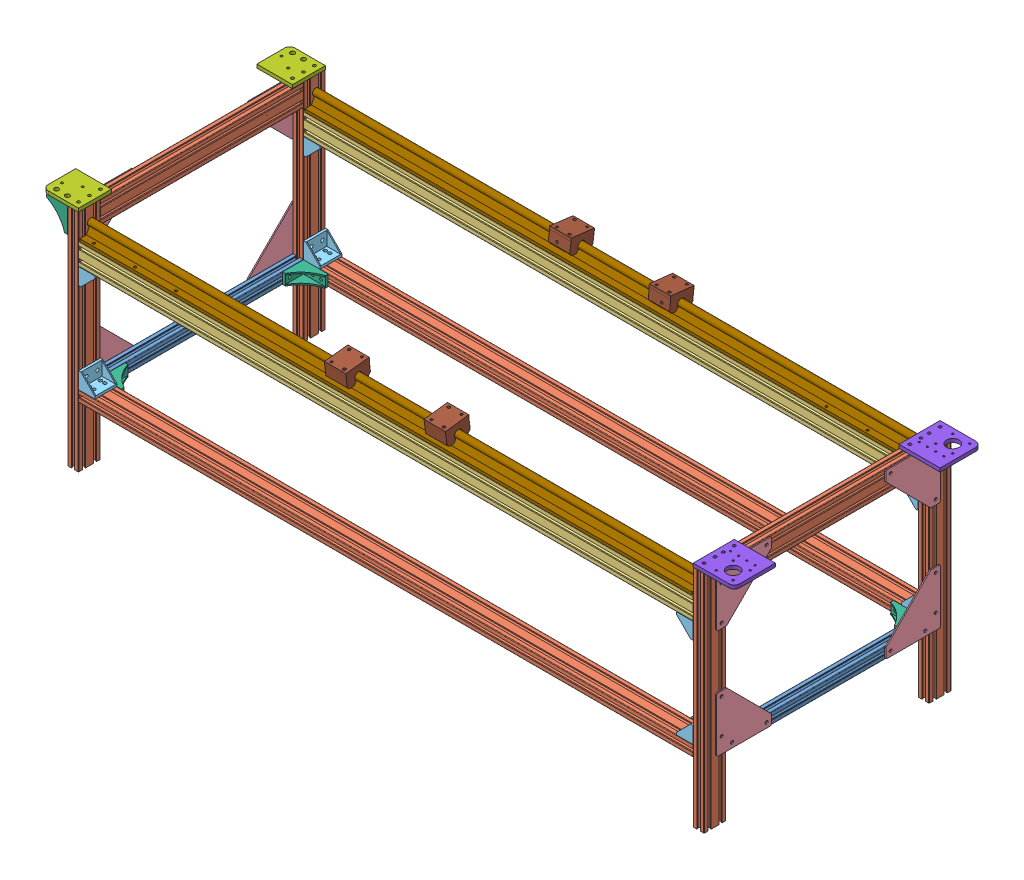
SolidWorks assembly SantaFe-Frame-Assy, configuration Default. Lengths in mm.
Overall size (1260 416.35 457.22).
69 component instances, 12 part files, 120 mates.
Components (placement in the parent):
- HFS5-2020-1: HFS5-2020 [370mm] at (0 110 0) size (20 20 370)
- HFS5-2020-2: HFS5-2020 [370mm] at (1140 110 0) size (20 20 370)
- HFS5-2040-7: HFS5-2040 [1120] at (1130 110 -20) x (0 -1 0) z (1 0 0) size (20 40 1120)
- HFS5-2040-8: HFS5-2040 [1120] at (10 110 390) x (0 1 0) z (-1 0 0) size (20 40 1120)
- HFS5-2040-1: HFS5-2040 [370mm] at (1140 380 370) size (20 40 370)
- HFS5-2040-2: HFS5-2040 [370mm] at (0 380 370) size (20 40 370)
- HFS5-4040-1120-1: HFS5-4040-1120 [Default] at (1130 334.5 390) x (0 0 -1) z (1 0 0) size (40 40 1120)
- HFS5-4040-1120-2: HFS5-4040-1120 [Default] at (1130 334.5 -20) x (0 0 -1) z (1 0 0) size (40 40 1120)
- HFS5-2040-3: HFS5-2040 [410mm] at (1140 400 390) x (1 0 0) z (0 1 0) size (20 40 410)
- HFS5-2040-4: HFS5-2040 [410mm] at (1140 -10 -20) x (1 0 0) z (0 -1 0) size (20 40 410)
- HFS5-2040-5: HFS5-2040 [410mm] at (0 -10 390) x (1 0 0) z (0 -1 0) size (20 40 410)
- HFS5-2040-6: HFS5-2040 [410mm] at (0 -10 -20) x (1 0 0) z (0 -1 0) size (20 40 410)
- SHPTCUL5-4: SHPTCUL5 [Default] at (1152 299 389) x (0 0 -1) z (1 0 0) size (100 100 2)
  - SHPTCUL5_Dummy-1: SHPTCUL5_Dummy [Default] at origin size (100 100 2)
- SHPTCUL5-5: SHPTCUL5 [Default] at (-10 299 389) x (0 0 -1) z (1 0 0) size (100 100 2)
  - SHPTCUL5_Dummy-1: SHPTCUL5_Dummy [Default] at origin size (100 100 2)
- SHPTCUL5-6: SHPTCUL5 [Default] at (1152 399 81) x (0 -1 0) z (1 0 0) size (100 100 2)
  - SHPTCUL5_Dummy-1: SHPTCUL5_Dummy [Default] at origin size (100 100 2)
- SHPTCUL5-7: SHPTCUL5 [Default] at (1152 101 289) x (0 1 0) z (1 0 0) size (100 100 2)
  - SHPTCUL5_Dummy-1: SHPTCUL5_Dummy [Default] at origin size (100 100 2)
- SHPTCUL5-8: SHPTCUL5 [Default] at (1152 201 -19) x (0 0 1) z (1 0 0) size (100 100 2)
  - SHPTCUL5_Dummy-1: SHPTCUL5_Dummy [Default] at origin size (100 100 2)
- SHPTCUL5-9: SHPTCUL5 [Default] at (-10 399 81) x (0 -1 0) z (1 0 0) size (100 100 2)
  - SHPTCUL5_Dummy-1: SHPTCUL5_Dummy [Default] at origin size (100 100 2)
- SHPTCUL5-10: SHPTCUL5 [Default] at (-10 201 -19) x (0 0 1) z (1 0 0) size (100 100 2)
  - SHPTCUL5_Dummy-1: SHPTCUL5_Dummy [Default] at origin size (100 100 2)
- SHPTCUL5-11: SHPTCUL5 [Default] at (-10 101 289) x (0 1 0) z (1 0 0) size (100 100 2)
  - SHPTCUL5_Dummy-1: SHPTCUL5_Dummy [Default] at origin size (100 100 2)
- Corner-Bracket-HBLFSDK5-1: Corner-Bracket-HBLFSDK5 [Default] at (1130 120 -20) x (0 0 1) z (-1 0 0) size (40 30 30)
- Corner-Bracket-HBLFSDK5-2: Corner-Bracket-HBLFSDK5 [Default] at (1130 120 390) x (0 0 1) z (-1 0 0) size (40 30 30)
- Corner-Bracket-HBLFSDK5-3: Corner-Bracket-HBLFSDK5 [Default] at (1130 314.5 390) x (0 0 1) z (0 -1 0) size (40 30 30)
- Corner-Bracket-HBLFSDK5-4: Corner-Bracket-HBLFSDK5 [Default] at (1130 314.5 -20) x (0 0 1) z (0 -1 0) size (40 30 30)
- Corner-Bracket-HBLFSDK5-5: Corner-Bracket-HBLFSDK5 [Default] at (10 314.5 -20) x (0 0 -1) z (0 -1 0) size (40 30 30)
- Corner-Bracket-HBLFSDK5-6: Corner-Bracket-HBLFSDK5 [Default] at (10 314.5 390) x (0 0 -1) z (0 -1 0) size (40 30 30)
- Corner-Bracket-HBLFSDK5-7: Corner-Bracket-HBLFSDK5 [Default] at (10 120 -20) x (0 0 -1) z (1 0 0) size (40 30 30)
- Corner-Bracket-HBLFSDK5-8: Corner-Bracket-HBLFSDK5 [Default] at (10 120 390) x (0 0 -1) z (1 0 0) size (40 30 30)
- HBLFSSW5-3: HBLFSSW5 [Default] at (10 110 370) x (0 -1 0) z (1 0 0) size (20 45.8 38.8)
  - HBLFSSW5hblfsn5-1: HBLFSSW5hblfsn5 [Default] at origin size (20 45.8 38.8)
- HBLFSSW5-4: HBLFSSW5 [Default] at (10 110 0) x (0 -1 0) z (0 0 1) size (20 45.8 38.8)
  - HBLFSSW5hblfsn5-1: HBLFSSW5hblfsn5 [Default] at origin size (20 45.8 38.8)
- HBLFSSW5-5: HBLFSSW5 [Default] at (1130 110 0) x (0 1 0) z (0 0 1) size (20 45.8 38.8)
  - HBLFSSW5hblfsn5-1: HBLFSSW5hblfsn5 [Default] at origin size (20 45.8 38.8)
- HBLFSSW5-6: HBLFSSW5 [Default] at (1130 110 370) x (0 -1 0) z (0 0 -1) size (20 45.8 38.8)
  - HBLFSSW5hblfsn5-1: HBLFSSW5hblfsn5 [Default] at origin size (20 45.8 38.8)
- HBLFSSW5-7: HBLFSSW5 [Default] at (-10 400 400) x (0 0 -1) z (-1 0 0) size (20 45.8 38.8)
  - HBLFSSW5hblfsn5-1: HBLFSSW5hblfsn5 [Default] at origin size (20 45.8 38.8)
- HBLFSSW5-8: HBLFSSW5 [Default] at (-10 400 -30) x (0 0 -1) z (-1 0 0) size (20 45.8 38.8)
  - HBLFSSW5hblfsn5-1: HBLFSSW5hblfsn5 [Default] at origin size (20 45.8 38.8)
- Idler-Plate-1: Idler-Plate [Default] at (10 406.35 20) x (0 0 -1) z (-1 0 0) size (60 6.35 65)
- Idler-Plate-2: Idler-Plate [Default] at (10 400 350) x (0 0 1) z (-1 0 0) size (60 6.35 65)
- Stepper-Plate-1: Stepper-Plate [Default] at (1130 400 35) x (0 0 -1) z (1 0 0) size (75 6.35 75)
- Stepper-Plate-2: Stepper-Plate [Default] at (1130 406.35 335) x (0 0 1) z (1 0 0) size (75 6.35 75)
- X-Axis-Slide-Assy-1: X-Axis-Slide-Assy [Default] at (202.5 376.5 390) x (0 0 1) z (0 1 0) size (46.21 1115 42.58) (flexible)
  - AWMU-12-1: AWMU-12 [Default] at origin size (40 1115 28)
  - OJUM-06-12-1: OJUM-06-12 [Mirror] at (0 460.2515 0) x (-0.991917 0 0.126885) z (-0.126885 0 -0.991917) size (43 39 28)
    - OJUM-06-12-1: OJUM-06-12 [Default] at origin size (15.6 31 13.94)
    - OJUM-06-12_1-1: OJUM-06-12_1 [Mirror] at origin size (43 39 28)
  - OJUM-06-12-2: OJUM-06-12 [Default] at (0 278.4523 0) x (-0.99383 0 0.110917) z (-0.110917 0 -0.99383) size (43 39 28)
    - OJUM-06-12-1: OJUM-06-12 [Default] at origin size (15.6 31 13.94)
    - OJUM-06-12_1-1: OJUM-06-12_1 [Default] at origin size (43 39 28)
- X-Axis-Slide-Assy-2: X-Axis-Slide-Assy [Default] at (937.5 376.5 -20) x (0 0 -1) z (0 1 0) size (46.21 1115 42.58) (flexible)
  - AWMU-12-1: AWMU-12 [Default] at origin size (40 1115 28)
  - OJUM-06-12-1: OJUM-06-12 [Mirror] at (0 460.2515 0) x (-0.991917 0 0.126885) z (-0.126885 0 -0.991917) size (43 39 28)
    - OJUM-06-12-1: OJUM-06-12 [Default] at origin size (15.6 31 13.94)
    - OJUM-06-12_1-1: OJUM-06-12_1 [Mirror] at origin size (43 39 28)
  - OJUM-06-12-2: OJUM-06-12 [Default] at (0 278.4523 0) x (-0.99383 0 0.110917) z (-0.110917 0 -0.99383) size (43 39 28)
    - OJUM-06-12-1: OJUM-06-12 [Default] at origin size (15.6 31 13.94)
    - OJUM-06-12_1-1: OJUM-06-12_1 [Default] at origin size (43 39 28)
- SpacerStick-1: SpacerStick [Default] at (60 217.25 -36.825) x (-1 0 0) z (0 0 -1) size (65 194.5 3.17) (hidden)
Mates (geometry in assembly coordinates):
- Coincident13: coincident anti-aligned: plane of HFS5-2020-2 through (1130 113.3 370) normal (-1 0 0); plane of HFS5-2040-8 through (1130 101 409) normal (1 0 0)
- Coincident57: coincident aligned: plane of HFS5-4040-1120-1 through (10 314.5 397) normal (0 -1 0); plane of HFS5-4040-1120-2 through (10 314.5 -13) normal (0 -1 0)
- Coincident58: coincident anti-aligned: plane of HFS5-2040-8 through (1130 101 409) normal (1 0 0); plane of HFS5-2040-3 through (1130 -10 383) normal (-1 0 0)
- Coincident60: coincident anti-aligned: plane of HFS5-2020-2 through (1136.5 109.3464 370) normal (0 0 1); plane of HFS5-2040-3 through (1137 -10 370) normal (0 0 -1)
- Coincident62: coincident anti-aligned: plane of HFS5-4040-1120-1 through (1130 315.5 409) normal (1 0 0); plane of HFS5-2040-3 through (1130 -10 383) normal (-1 0 0)
- Coincident63: coincident aligned: plane of HFS5-4040-1120-1 through (10 341.5 410) normal (0 0 1); plane of HFS5-2040-3 through (1131 -10 410) normal (0 0 1)
- Coincident64: coincident anti-aligned: plane of HFS5-2040-1 through (1131 361 370) normal (0 0 1); plane of HFS5-2040-3 through (1137 -10 370) normal (0 0 -1)
- Coincident65: coincident aligned: plane of HFS5-2040-1 through (1150 373 0) normal (1 0 0); plane of HFS5-2040-3 through (1150 -10 377) normal (1 0 0)
- Coincident66: coincident aligned: plane of HFS5-2040-1 through (1137 400 0) normal (0 1 0); plane of HFS5-2040-3 through (1131 400 409) normal (0 1 0)
- Coincident67: coincident anti-aligned: plane of HFS5-2020-2 through (1136.5 109.3464 0) normal (0 0 -1); plane of HFS5-2040-4 through (1137 400 0) normal (0 0 1)
- Coincident68: coincident aligned: plane of HFS5-2020-2 through (1150 113.3 370) normal (1 0 0); plane of HFS5-2040-4 through (1150 400 -27) normal (1 0 0)
- Coincident70: coincident anti-aligned: plane of HFS5-2020-1 through (-3.5 109.3464 370) normal (0 0 1); plane of HFS5-2040-5 through (3 400 370) normal (0 0 -1)
- Coincident71: coincident aligned: plane of HFS5-2020-1 through (-10 113.3 370) normal (-1 0 0); plane of HFS5-2040-5 through (-10 400 397) normal (-1 0 0)
- Coincident74: coincident anti-aligned: plane of HFS5-2040-8 through (10 101 409) normal (-1 0 0); plane of HFS5-2040-5 through (10 400 383) normal (1 0 0)
- Coincident76: coincident anti-aligned: plane of HFS5-2040-2 through (-9 361 0) normal (0 0 -1); plane of HFS5-2040-6 through (9 400 0) normal (0 0 1)
- Coincident77: coincident aligned: plane of HFS5-2040-2 through (9 400 0) normal (0 1 0); plane of HFS5-2040-5 through (-9 400 371) normal (0 1 0)
- Coincident78: coincident anti-aligned: plane of HFS5-2020-1 through (-3.5 109.3464 0) normal (0 0 -1); plane of HFS5-2040-6 through (-3 400 0) normal (0 0 1)
- Coincident79: coincident aligned: plane of HFS5-2020-1 through (-10 113.3 370) normal (-1 0 0); plane of HFS5-2040-6 through (-10 400 -13) normal (-1 0 0)
- Coincident81: coincident aligned: plane of HFS5-2040-7 through (10 113 -40) normal (0 0 -1); plane of HFS5-2040-6 through (3 400 -40) normal (0 0 -1)
- Coincident85: coincident anti-aligned: plane of HFS5-2040-7 through (10 119 -1) normal (-1 0 0); plane of HFS5-2040-6 through (10 400 -27) normal (1 0 0)
- Coincident86: coincident aligned: plane of HFS5-2040-2 through (-10 387 0) normal (-1 0 0); plane of HFS5-2040-5 through (-10 400 397) normal (-1 0 0)
- Distance2: distance = 45.5 mm aligned: plane of HFS5-2040-5 through (-9 400 371) normal (0 1 0); plane of HFS5-4040-1120-1 through (10 354.5 403) normal (0 1 0)
- Coincident88: coincident aligned: plane of HFS5-4040-1120-2 through (10 327.5 -40) normal (0 0 -1); plane of HFS5-2040-6 through (3 400 -40) normal (0 0 -1)
- Coincident89: coincident anti-aligned: plane of HFS5-4040-1120-2 through (10 315.5 -1) normal (-1 0 0); plane of HFS5-2040-6 through (10 400 -27) normal (1 0 0)
- Coincident108: coincident aligned: plane of HFS5-2040-8 through (1130 113 410) normal (0 0 1); plane of HFS5-2040-3 through (1131 -10 410) normal (0 0 1)
- Coincident111: coincident aligned: plane of HFS5-2040-7 through (10 113 -40) normal (0 0 -1); plane of HFS5-2040-4 through (1143 400 -40) normal (0 0 -1)
- Coincident113: coincident anti-aligned: plane of HFS5-2040-1 through (1150 373 0) normal (1 0 0); plane of SHPTCUL5-4/SHPTCUL5_Dummy-1 through (1150 299 389) normal (-1 0 0)
- Coincident114: coincident: line of HFS5-2040-1 through (1150 399 0) axis (0 0 1); plane of SHPTCUL5-4/SHPTCUL5_Dummy-1 through (1150 399 291) normal (0 1 0)
- Coincident115: coincident: line of HFS5-2040-3 through (1150 -10 371) axis (0 1 0); point of SHPTCUL5-4/SHPTCUL5_Dummy-1
- Coincident116: coincident anti-aligned: plane of HFS5-2040-5 through (-10 400 397) normal (-1 0 0); plane of SHPTCUL5-5/SHPTCUL5_Dummy-1 through (-10 299 389) normal (1 0 0)
- Coincident117: coincident: line of HFS5-2040-2 through (-10 399 0) axis (0 0 1); plane of SHPTCUL5-5/SHPTCUL5_Dummy-1 through (-12 399 291) normal (0 1 0)
- Coincident118: coincident: line of HFS5-2040-5 through (-10 400 371) axis (0 -1 0); point of SHPTCUL5-5/SHPTCUL5_Dummy-1
- Coincident119: coincident anti-aligned: plane of HFS5-2040-1 through (1150 373 0) normal (1 0 0); plane of SHPTCUL5-6/SHPTCUL5_Dummy-1 through (1150 399 81) normal (-1 0 0)
- Coincident122: coincident: line of HFS5-2040-1 through (1150 399 0) axis (0 0 1); plane of SHPTCUL5-6/SHPTCUL5_Dummy-1 through (1150 399 -17) normal (0 1 0)
- Coincident123: coincident: line of HFS5-2040-4 through (1150 400 -1) axis (0 -1 0); point of SHPTCUL5-6/SHPTCUL5_Dummy-1
- Coincident124: coincident anti-aligned: plane of HFS5-2040-3 through (1150 -10 397) normal (1 0 0); plane of SHPTCUL5-7/SHPTCUL5_Dummy-1 through (1150 101 289) normal (-1 0 0)
- Coincident125: coincident anti-aligned: plane of HFS5-2040-4 through (1150 400 -27) normal (1 0 0); plane of SHPTCUL5-8/SHPTCUL5_Dummy-1 through (1150 201 -19) normal (-1 0 0)
- Coincident126: coincident: line of HFS5-2020-2 through (1150 101 370) axis (0 0 -1); plane of SHPTCUL5-7/SHPTCUL5_Dummy-1 through (1150 101 387) normal (0 -1 0)
- Coincident127: coincident: line of HFS5-2040-3 through (1150 -10 371) axis (0 1 0); point of SHPTCUL5-7/SHPTCUL5_Dummy-1
- Coincident128: coincident: line of HFS5-2020-2 through (1150 101 370) axis (0 0 -1); plane of SHPTCUL5-8/SHPTCUL5_Dummy-1 through (1150 101 79) normal (0 -1 0)
- Coincident129: coincident: line of HFS5-2040-4 through (1150 400 -1) axis (0 -1 0); point of SHPTCUL5-8/SHPTCUL5_Dummy-1
- Coincident130: coincident anti-aligned: plane of HFS5-2040-2 through (-10 387 0) normal (-1 0 0); plane of SHPTCUL5-9/SHPTCUL5_Dummy-1 through (-10 399 81) normal (1 0 0)
- Coincident131: coincident: line of HFS5-2040-2 through (-10 399 0) axis (0 0 1); plane of SHPTCUL5-9/SHPTCUL5_Dummy-1 through (-12 399 -17) normal (0 1 0)
- Coincident132: coincident: line of HFS5-2040-6 through (-10 400 -1) axis (0 -1 0); point of SHPTCUL5-9/SHPTCUL5_Dummy-1
- Coincident133: coincident: line of HFS5-2020-1 through (-10 101 370) axis (0 0 -1); plane of SHPTCUL5-10/SHPTCUL5_Dummy-1 through (-12 101 79) normal (0 -1 0)
- Coincident134: coincident anti-aligned: plane of HFS5-2020-1 through (-10 106.7 370) normal (-1 0 0); plane of SHPTCUL5-10/SHPTCUL5_Dummy-1 through (-10 201 -19) normal (1 0 0)
- Coincident135: coincident: line of HFS5-2040-6 through (-10 400 -1) axis (0 -1 0); point of SHPTCUL5-10/SHPTCUL5_Dummy-1
- Coincident136: coincident anti-aligned: plane of HFS5-2040-5 through (-10 400 397) normal (-1 0 0); plane of SHPTCUL5-11/SHPTCUL5_Dummy-1 through (-10 101 289) normal (1 0 0)
- Coincident137: coincident: line of HFS5-2020-1 through (-10 101 370) axis (0 0 -1); plane of SHPTCUL5-11/SHPTCUL5_Dummy-1 through (-12 101 387) normal (0 -1 0)
- Coincident138: coincident: line of HFS5-2040-5 through (-10 400 371) axis (0 -1 0); point of SHPTCUL5-11/SHPTCUL5_Dummy-1
- Coincident139: coincident anti-aligned: plane of HFS5-2040-4 through (1130 400 -13) normal (-1 0 0); plane of Corner-Bracket-HBLFSDK5-4 through (1130 284.5 0) normal (1 0 0)
- Coincident140: coincident anti-aligned: plane of HFS5-4040-1120-2 through (10 314.5 -13) normal (0 -1 0); plane of Corner-Bracket-HBLFSDK5-4 through (1130 314.5 0) normal (0 1 0)
- Coincident141: coincident aligned: plane of HFS5-4040-1120-2 through (10 327.5 -40) normal (0 0 -1); plane of Corner-Bracket-HBLFSDK5-4 through (1130 314.5 -40) normal (0 0 -1)
- Coincident142: coincident aligned: plane of HFS5-2040-4 through (1131 400 -40) normal (0 0 -1); plane of Corner-Bracket-HBLFSDK5-1 through (1130 120 -40) normal (0 0 -1)
- Coincident143: coincident anti-aligned: plane of HFS5-2040-4 through (1130 400 -13) normal (-1 0 0); plane of Corner-Bracket-HBLFSDK5-1 through (1130 120 0) normal (1 0 0)
- Coincident144: coincident anti-aligned: plane of HFS5-2040-7 through (10 120 -27) normal (0 1 0); plane of Corner-Bracket-HBLFSDK5-1 through (1100 120 0) normal (0 -1 0)
- Coincident145: coincident anti-aligned: plane of HFS5-2040-3 through (1130 -10 383) normal (-1 0 0); plane of Corner-Bracket-HBLFSDK5-2 through (1130 120 410) normal (1 0 0)
- Coincident146: coincident anti-aligned: plane of HFS5-2040-8 through (1130 120 397) normal (0 1 0); plane of Corner-Bracket-HBLFSDK5-2 through (1100 120 410) normal (0 -1 0)
- Coincident147: coincident aligned: plane of HFS5-2040-3 through (1131 -10 410) normal (0 0 1); plane of Corner-Bracket-HBLFSDK5-2 through (1130 120 410) normal (0 0 1)
- Coincident148: coincident anti-aligned: plane of HFS5-2040-3 through (1130 -10 383) normal (-1 0 0); plane of Corner-Bracket-HBLFSDK5-3 through (1130 284.5 410) normal (1 0 0)
- Coincident149: coincident anti-aligned: plane of HFS5-4040-1120-1 through (10 314.5 397) normal (0 -1 0); plane of Corner-Bracket-HBLFSDK5-3 through (1130 314.5 410) normal (0 1 0)
- Coincident150: coincident aligned: plane of HFS5-4040-1120-1 through (10 341.5 410) normal (0 0 1); plane of Corner-Bracket-HBLFSDK5-3 through (1130 314.5 410) normal (0 0 1)
- Coincident151: coincident anti-aligned: plane of HFS5-2040-8 through (1130 120 397) normal (0 1 0); plane of Corner-Bracket-HBLFSDK5-8 through (40 120 370) normal (0 -1 0)
- Coincident152: coincident anti-aligned: plane of HFS5-2040-5 through (10 400 383) normal (1 0 0); plane of Corner-Bracket-HBLFSDK5-8 through (10 120 370) normal (-1 0 0)
- Coincident153: coincident aligned: plane of HFS5-2040-8 through (1130 113 410) normal (0 0 1); plane of Corner-Bracket-HBLFSDK5-8 through (10 120 410) normal (0 0 1)
- Coincident154: coincident anti-aligned: plane of HFS5-2040-7 through (10 120 -27) normal (0 1 0); plane of Corner-Bracket-HBLFSDK5-7 through (40 120 -40) normal (0 -1 0)
- Coincident155: coincident aligned: plane of HFS5-2040-7 through (10 113 -40) normal (0 0 -1); plane of Corner-Bracket-HBLFSDK5-7 through (10 120 -40) normal (0 0 -1)
- Coincident156: coincident anti-aligned: plane of HFS5-2040-6 through (10 400 -27) normal (1 0 0); plane of Corner-Bracket-HBLFSDK5-7 through (10 120 -40) normal (-1 0 0)
- Coincident157: coincident anti-aligned: plane of HFS5-4040-1120-2 through (10 314.5 -33) normal (0 -1 0); plane of Corner-Bracket-HBLFSDK5-5 through (10 314.5 -40) normal (0 1 0)
- Coincident158: coincident anti-aligned: plane of HFS5-2040-6 through (10 400 -27) normal (1 0 0); plane of Corner-Bracket-HBLFSDK5-5 through (10 284.5 -40) normal (-1 0 0)
- Coincident159: coincident aligned: plane of HFS5-2040-6 through (-9 400 -40) normal (0 0 -1); plane of Corner-Bracket-HBLFSDK5-5 through (10 314.5 -40) normal (0 0 -1)
- Coincident160: coincident anti-aligned: plane of HFS5-4040-1120-1 through (10 314.5 397) normal (0 -1 0); plane of Corner-Bracket-HBLFSDK5-6 through (10 314.5 370) normal (0 1 0)
- Coincident161: coincident anti-aligned: plane of HFS5-2040-5 through (10 400 383) normal (1 0 0); plane of Corner-Bracket-HBLFSDK5-6 through (10 284.5 370) normal (-1 0 0)
- Coincident162: coincident aligned: plane of HFS5-4040-1120-1 through (10 341.5 410) normal (0 0 1); plane of Corner-Bracket-HBLFSDK5-6 through (10 314.5 410) normal (0 0 1)
- Coincident188: coincident aligned: plane of HFS5-2040-8 through (1130 120 397) normal (0 1 0); plane of HBLFSSW5-3/HBLFSSW5hblfsn5-1 through (14.5286 120 326) normal (0 1 0)
- Coincident189: coincident anti-aligned: plane of HFS5-2020-1 through (10 106.7 370) normal (1 0 0); plane of HBLFSSW5-3/HBLFSSW5hblfsn5-1 through (10 110 370) normal (-1 0 0)
- Coincident190: coincident anti-aligned: plane of HFS5-2040-8 through (1130 119 370) normal (0 0 -1); plane of HBLFSSW5-3/HBLFSSW5hblfsn5-1 through (9.2 120 370) normal (0 0 1)
- Coincident191: coincident aligned: plane of HFS5-2040-7 through (10 120 -27) normal (0 1 0); plane of HBLFSSW5-4/HBLFSSW5hblfsn5-1 through (54 120 4.5286) normal (0 1 0)
- Coincident192: coincident anti-aligned: plane of HFS5-2020-1 through (10 106.7 370) normal (1 0 0); plane of HBLFSSW5-4/HBLFSSW5hblfsn5-1 through (10 120 -0.8) normal (-1 0 0)
- Coincident193: coincident anti-aligned: plane of HFS5-2040-7 through (10 119 0) normal (0 0 1); plane of HBLFSSW5-4/HBLFSSW5hblfsn5-1 through (10 110 0) normal (0 0 -1)
- Coincident194: coincident aligned: plane of HFS5-2040-8 through (1130 120 397) normal (0 1 0); plane of HBLFSSW5-6/HBLFSSW5hblfsn5-1 through (1086 120 365.4714) normal (0 1 0)
- Coincident195: coincident anti-aligned: plane of HFS5-2040-8 through (1130 119 370) normal (0 0 -1); plane of HBLFSSW5-6/HBLFSSW5hblfsn5-1 through (1130 110 370) normal (0 0 1)
- Coincident196: coincident anti-aligned: plane of HFS5-2020-2 through (1130 113.3 370) normal (-1 0 0); plane of HBLFSSW5-6/HBLFSSW5hblfsn5-1 through (1130 120 370.8) normal (1 0 0)
- Coincident197: coincident aligned: plane of HFS5-2040-7 through (10 120 -27) normal (0 1 0); plane of HBLFSSW5-5/HBLFSSW5hblfsn5-1 through (1086 120 4.5286) normal (0 1 0)
- Coincident198: coincident anti-aligned: plane of HFS5-2040-7 through (10 119 0) normal (0 0 1); plane of HBLFSSW5-5/HBLFSSW5hblfsn5-1 through (1130 110 0) normal (0 0 -1)
- Coincident199: coincident anti-aligned: plane of HFS5-2020-2 through (1130 113.3 370) normal (-1 0 0); plane of HBLFSSW5-5/HBLFSSW5hblfsn5-1 through (1130 100 -0.8) normal (1 0 0)
- Coincident200: coincident anti-aligned: plane of HFS5-2040-6 through (-10 400 -33) normal (-1 0 0); plane of HBLFSSW5-8/HBLFSSW5hblfsn5-1 through (-10 400 -30) normal (1 0 0)
- Coincident201: coincident aligned: plane of HFS5-2040-6 through (-9 400 -39) normal (0 1 0); plane of HBLFSSW5-8/HBLFSSW5hblfsn5-1 through (-9.2 400 -20) normal (0 1 0)
- Coincident202: coincident aligned: plane of HFS5-2040-6 through (-9 400 -40) normal (0 0 -1); plane of HBLFSSW5-8/HBLFSSW5hblfsn5-1 through (-14.5286 356 -40) normal (0 0 -1)
- Coincident203: coincident anti-aligned: plane of HFS5-2040-5 through (-10 400 409) normal (-1 0 0); plane of HBLFSSW5-7/HBLFSSW5hblfsn5-1 through (-10 400 400) normal (1 0 0)
- Coincident204: coincident aligned: plane of HFS5-2040-5 through (-9 400 371) normal (0 1 0); plane of HBLFSSW5-7/HBLFSSW5hblfsn5-1 through (-9.2 400 410) normal (0 1 0)
- Coincident205: coincident aligned: plane of HFS5-2040-5 through (-3 400 410) normal (0 0 1); plane of HBLFSSW5-7/HBLFSSW5hblfsn5-1 through (-14.5286 356 410) normal (0 0 1)
- Coincident206: coincident anti-aligned: plane of HFS5-2040-5 through (-9 400 371) normal (0 1 0); plane of Idler-Plate-2 through (10 400 350) normal (0 -1 0)
- Concentric2: concentric aligned: cylinder of HFS5-2040-5 through (0 1190 400) axis (0 -1 0) radius 2.1; cylinder of Idler-Plate-2 through (0 406.35 400) axis (0 -1 0) radius 2.625
- Concentric3: concentric aligned: cylinder of HFS5-2040-5 through (0 1190 380) axis (0 -1 0) radius 2.1; cylinder of Idler-Plate-2 through (0 406.35 380) axis (0 -1 0) radius 2.625
- Coincident207: coincident anti-aligned: plane of HFS5-2040-6 through (-9 400 -39) normal (0 1 0); plane of Idler-Plate-1 through (10 400 20) normal (0 -1 0)
- Concentric4: concentric anti-aligned: cylinder of HFS5-2040-6 through (0 1190 -30) axis (0 -1 0) radius 2.1; cylinder of Idler-Plate-1 through (0 400 -30) axis (0 1 0) radius 2.625
- Concentric5: concentric anti-aligned: cylinder of HFS5-2040-6 through (0 1190 -10) axis (0 -1 0) radius 2.1; cylinder of Idler-Plate-1 through (0 400 -10) axis (0 1 0) radius 2.625
- Coincident208: coincident anti-aligned: plane of HFS5-2040-4 through (1131 400 -39) normal (0 1 0); plane of Stepper-Plate-1 through (1130 400 35) normal (0 -1 0)
- Concentric6: concentric aligned: cylinder of HFS5-2040-4 through (1140 1190 -30) axis (0 -1 0) radius 2.1; cylinder of Stepper-Plate-1 through (1140 406.35 -30) axis (0 -1 0) radius 2.625
- Concentric7: concentric aligned: cylinder of HFS5-2040-4 through (1140 1190 -10) axis (0 -1 0) radius 2.1; cylinder of Stepper-Plate-1 through (1140 406.35 -10) axis (0 -1 0) radius 2.625
- Coincident209: coincident anti-aligned: plane of HFS5-2040-3 through (1131 400 409) normal (0 1 0); plane of Stepper-Plate-2 through (1130 400 335) normal (0 -1 0)
- Concentric8: concentric aligned: cylinder of HFS5-2040-3 through (1140 -800 400) axis (0 1 0) radius 2.1; cylinder of Stepper-Plate-2 through (1140 400 400) axis (0 1 0) radius 2.625
- Concentric9: concentric aligned: cylinder of HFS5-2040-3 through (1140 -800 380) axis (0 1 0) radius 2.1; cylinder of Stepper-Plate-2 through (1140 400 380) axis (0 1 0) radius 2.625
- Coincident210: coincident aligned: plane of HFS5-2040-1 through (1137 400 0) normal (0 1 0); plane of HFS5-2040-4 through (1131 400 -39) normal (0 1 0)
- Coincident214: coincident aligned: plane of HFS5-2040-3 through (1131 400 409) normal (0 1 0); plane of HFS5-2040-5 through (-9 400 371) normal (0 1 0)
- Coincident215: coincident aligned: plane of HFS5-2040-2 through (9 400 0) normal (0 1 0); plane of HFS5-2040-6 through (-9 400 -39) normal (0 1 0)
- Coincident216: coincident aligned: plane of HFS5-2020-1 through (-3.3 100 370) normal (0 -1 0); plane of HBLFSSW5-3/HBLFSSW5hblfsn5-1 through (14.5286 100 326) normal (0 -1 0)
- Coincident217: coincident aligned: plane of HFS5-2020-1 through (3.3 100 370) normal (0 -1 0); plane of HBLFSSW5-4/HBLFSSW5hblfsn5-1 through (54 100 4.5286) normal (0 -1 0)
- Coincident218: coincident aligned: plane of HFS5-2020-2 through (1136.7 100 370) normal (0 -1 0); plane of HBLFSSW5-5/HBLFSSW5hblfsn5-1 through (1086 100 4.5286) normal (0 -1 0)
- Distance3: distance = 110 mm aligned: plane of HFS5-2040-8 through (1130 100 383) normal (0 -1 0); plane of HFS5-2040-5 through (-9 -10 371) normal (0 -1 0)
- Coincident219: coincident anti-aligned: plane of HFS5-4040-1120-1 through (10 354.5 403) normal (0 1 0); plane of X-Axis-Slide-Assy-1/AWMU-12-1 through (202.5 354.5 390) normal (0 -1 0)
- Coincident220: coincident aligned: plane of HFS5-4040-1120-1 through (10 353.5 410) normal (0 0 1); plane of X-Axis-Slide-Assy-1/AWMU-12-1 through (202.5 359.5 410) normal (0 0 1)
- Distance4: distance = 2.5 mm anti-aligned: plane of HFS5-2040-5 through (10 400 383) normal (1 0 0); plane of X-Axis-Slide-Assy-1/AWMU-12-1 through (12.5 360.3407 390) normal (-1 0 0)
- Coincident222: coincident anti-aligned: plane of HFS5-4040-1120-2 through (10 354.5 -39) normal (0 1 0); plane of X-Axis-Slide-Assy-2/AWMU-12-1 through (937.5 354.5 -20) normal (0 -1 0)
- Coincident223: coincident aligned: plane of HFS5-4040-1120-2 through (10 347.5 -40) normal (0 0 -1); plane of X-Axis-Slide-Assy-2/AWMU-12-1 through (937.5 359.5 -40) normal (0 0 -1)
- Distance6: distance = 2.5 mm anti-aligned: plane of X-Axis-Slide-Assy-2/AWMU-12-1 through (1127.5 360.3407 -20) normal (1 0 0); plane of HFS5-2040-4 through (1130 400 -13) normal (-1 0 0)
- Coincident224: coincident anti-aligned: plane of HFS5-2040-7 through (10 120 -39) normal (0 1 0); plane of SpacerStick-1 through (75 120 -40) normal (0 -1 0)
- Coincident225: coincident anti-aligned: plane of HFS5-2040-6 through (10 400 -39) normal (1 0 0); plane of SpacerStick-1 through (10 290.65 114.0897) normal (-1 0 0)
- Coincident226: coincident aligned: plane of HFS5-2040-6 through (3 400 -40) normal (0 0 -1); plane of SpacerStick-1 through (60 217.25 -40) normal (0 0 -1)
